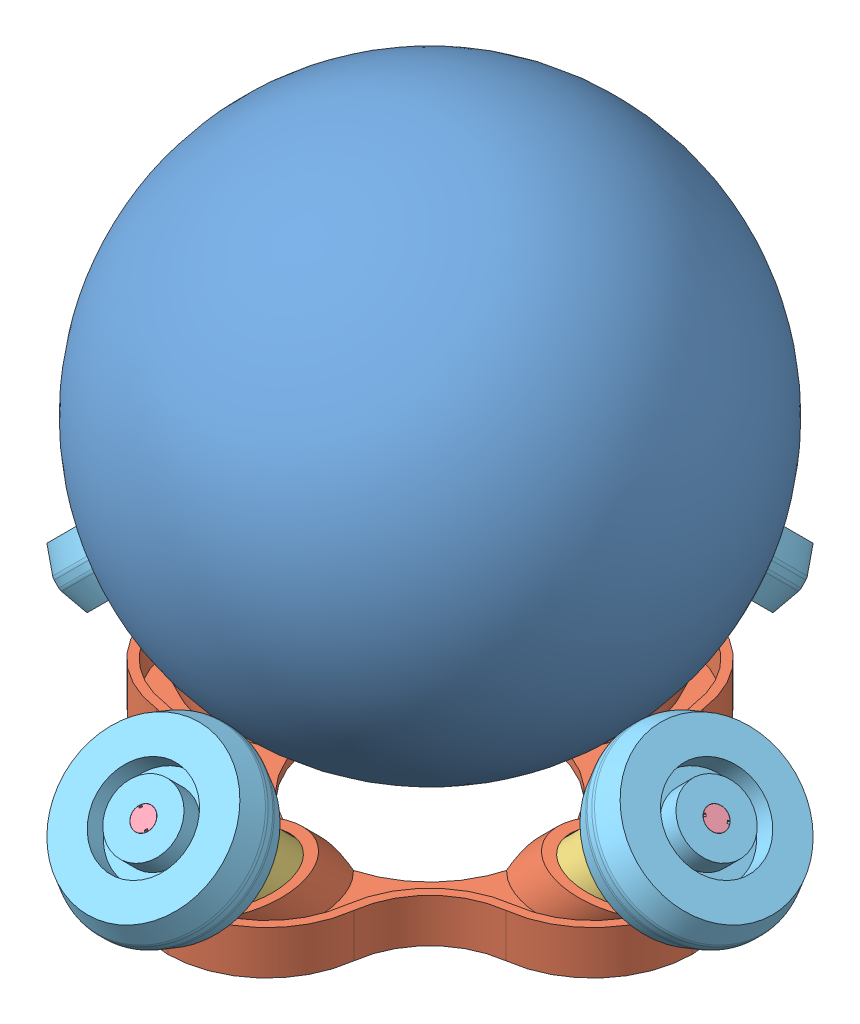
SolidWorks assembly Assem3, configuration Default. Lengths in mm.
Overall size (202.53 193.11 202.53).
19 component instances, 5 part files, 4 mates.
Components (placement in the parent):
- Basketball-1: Basketball [Default] at (96.1875 101.3412 200.3668) size (152.4 152.4 152.4)
- SimpleBaseASM-1: SimpleBaseASM [Default] at (63.276 -45.6909 120.9491) size (202.53 75.33 202.53)
  - SimpleBase-1: SimpleBase [Default] at (32.9115 49.7278 79.4177) size (152.4 15.38 152.4)
  - SimpleMotorASM-1: SimpleMotorASM [Default] at (-20.3302 21.8371 63.1777) x (0 0 1) z (-0.707107 0.707107 0) size (50.8 50.8 56.46)
    - DC_Motor-1: DC_Motor [Default] at (16.24 25.168 15.283) size (24.38 24.38 45.03)
    - MotorShaft-1: MotorShaft [Default] at (16.24 25.168 67.6832) x (0.749535 -0.661965 0) z (0.661965 0.749535 0) size (6.3 19.05 6.35)
    - Omni_Wheel-1: Omni_Wheel [Default] at (16.24 25.168 59.4282) size (50.8 50.8 16.51)
  - SimpleMotorASM-2: SimpleMotorASM [Default] at (49.1515 21.8371 26.1759) x (-1 0 0) z (0 0.707107 -0.707107) size (50.8 50.8 56.46)
    - DC_Motor-1: DC_Motor [Default] at (16.24 25.168 15.283) size (24.38 24.38 45.03)
    - MotorShaft-1: MotorShaft [Default] at (16.24 25.168 67.6832) x (0.749535 -0.661965 0) z (0.661965 0.749535 0) size (6.3 19.05 6.35)
    - Omni_Wheel-1: Omni_Wheel [Default] at (16.24 25.168 59.4282) size (50.8 50.8 16.51)
  - SimpleMotorASM-3: SimpleMotorASM [Default] at (86.1533 21.8371 95.6576) x (0 0 -1) z (0.707107 0.707107 0) size (50.8 50.8 56.46)
    - DC_Motor-1: DC_Motor [Default] at (16.24 25.168 15.283) size (24.38 24.38 45.03)
    - MotorShaft-1: MotorShaft [Default] at (16.24 25.168 67.6832) x (0.749535 -0.661965 0) z (0.661965 0.749535 0) size (6.3 19.05 6.35)
    - Omni_Wheel-1: Omni_Wheel [Default] at (16.24 25.168 59.4282) size (50.8 50.8 16.51)
  - SimpleMotorASM-4: SimpleMotorASM [Default] at (16.6716 21.8371 132.6594) x (1 0 0) z (0 0.707107 0.707107) size (50.8 50.8 56.46)
    - DC_Motor-1: DC_Motor [Default] at (16.24 25.168 15.283) size (24.38 24.38 45.03)
    - MotorShaft-1: MotorShaft [Default] at (16.24 25.168 67.6832) x (0.749535 -0.661965 0) z (0.661965 0.749535 0) size (6.3 19.05 6.35)
    - Omni_Wheel-1: Omni_Wheel [Default] at (16.24 25.168 59.4282) size (50.8 50.8 16.51)
Mates (geometry in assembly coordinates):
- Distance1: distance = 45.72 mm aligned: plane of SimpleBaseASM-1/SimpleBase-1 through (48.867 -65.6638 200.3668) normal (0 -1 0); sphere of Basketball-1
- Concentric2: concentric: sphere of Basketball-1; cylinder of SimpleBaseASM-1/SimpleBase-1 through (96.1875 16.7379 200.3668) axis (0 -1 0) radius 31.75
- Tangent6: tangent: sphere of Basketball-1; circle of SimpleBaseASM-1/SimpleMotorASM-3/Omni_Wheel-1
- Tangent7: tangent: sphere of Basketball-1; circle of SimpleBaseASM-1/SimpleMotorASM-1/Omni_Wheel-1
